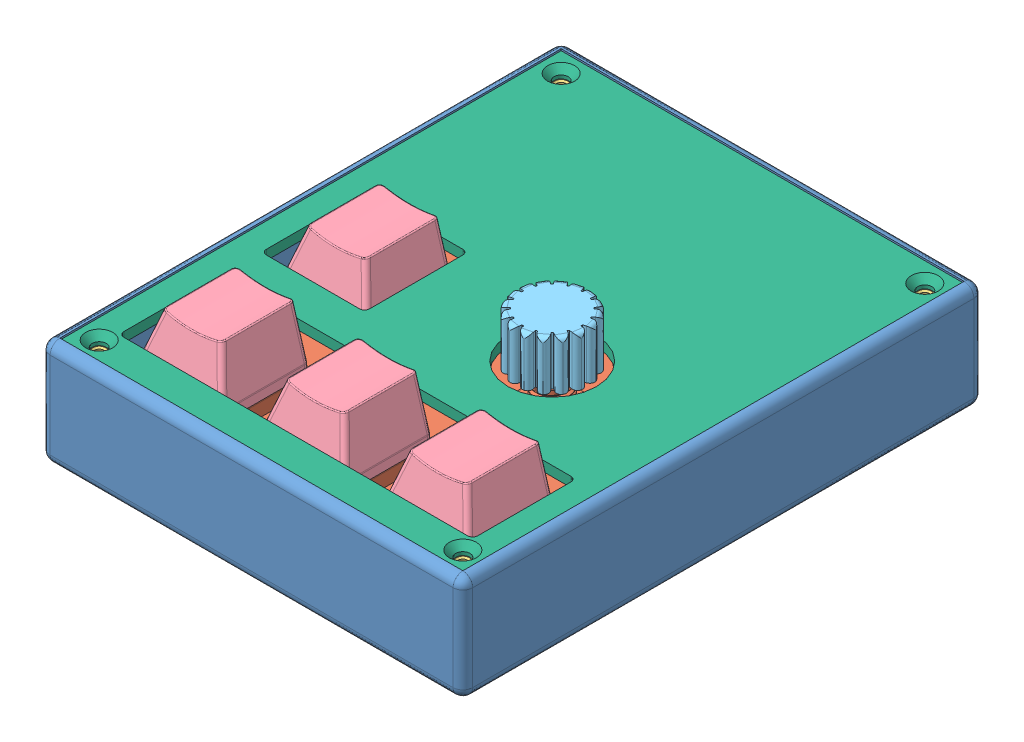
SolidWorks assembly DeviceAssembly, configuration Default. Lengths in mm.
Overall size (86 40.81 106).
12 component instances, 6 part files, 28 mates.
Components (placement in the parent):
- Box-1: Box [Default] at (-7.8946 4.0891 -4.0473) size (86 21.6 106)
- PCB-1: PCB [Default] at (-47.8946 11.3353 -54.0503) x (1 0 0) z (0 1 0) size (80 100.71 38.82)
- Standoff-1: Standoff [Default] at (-44.8946 21.3353 -51.0473) x (-0.059486 0 0.998229) z (0 -1 0) size (5.78 5.78 16)
- Standoff-13: Standoff [Default] at (-44.8946 21.3353 42.9527) x (0.129701 0 0.991553) z (0 -1 0) size (5.78 5.78 16)
- Standoff-15: Standoff [Default] at (29.1054 21.3353 42.9527) x (0.340404 0 0.940279) z (0 -1 0) size (5.78 5.78 16)
- Standoff-17: Standoff [Default] at (29.1054 21.3353 -51.0473) x (0.551349 0 0.834275) z (0 -1 0) size (5.78 5.78 16)
- Keycap-1: Keycap [Default] at (-42.1246 16.9831 -8.5326) x (1 0 0) z (0 0 1) size (18 11.34 18.01)
- Keycap-2: Keycap [Default] at (-42.1246 16.9831 20.8162) x (1 0 0) z (0 0 1) size (18 11.34 18.01)
- Keycap-4: Keycap [Default] at (-17.1246 16.9831 20.8162) x (1 0 0) z (0 0 1) size (18 11.34 18.01)
- Keycap-6: Keycap [Default] at (7.8754 16.9831 20.8162) x (1 0 0) z (0 0 1) size (18 11.34 18.01)
- Knob cap-1: Knob cap [Default] at (-22.2739 22.648 -63.0567) x (-0.249245 0 -0.96844) z (0 1 0) size (14.94 14.94 10)
- Lid-1: Lid [Default] at (0.6036 21.3353 0.6796) x (1 0 0) z (0 1 0) size (82 102 2)
Mates (geometry in assembly coordinates):
- Distance1: distance = 1 mm anti-aligned: plane of PCB-1 through (-47.8946 10.0891 42.9527) normal (-1 0 0); plane of Box-1 through (-48.8946 23.6891 -55.0473) normal (1 0 0)
- Distance2: distance = 1 mm anti-aligned: plane of PCB-1 through (-44.8946 10.0891 -54.0473) normal (0 0 -1); plane of Box-1 through (-48.8946 23.6891 -55.0473) normal (0 0 1)
- Distance3: distance = 0 mm anti-aligned: plane of PCB-1 through (-7.8946 10.0891 -4.0475) normal (0 -1 0); plane of Box-1 through (-7.8946 10.0891 -4.0473) normal (0 1 0)
- Concentric3: concentric aligned: cylinder of Box-1 through (-44.8946 10.0891 -51.0473) axis (0 -1 0) radius 1.85; cylinder of Standoff-1 through (-44.8946 21.3353 -51.0473) axis (0 -1 0) radius 1.25
- Coincident8: coincident anti-aligned: plane of PCB-1 through (-7.8946 11.3353 -4.0475) normal (0 1 0); plane of Standoff-1 through (-44.8946 11.3353 -51.0473) normal (0 -1 0)
- Concentric9: concentric aligned: cylinder of Box-1 through (-44.8946 10.0891 42.9527) axis (0 -1 0) radius 1.85; cylinder of Standoff-13 through (-44.8946 21.3353 42.9527) axis (0 -1 0) radius 1.25
- Coincident19: coincident anti-aligned: plane of PCB-1 through (-7.8946 11.3353 -4.0475) normal (0 1 0); plane of Standoff-13 through (-44.8946 11.3353 42.9527) normal (0 -1 0)
- Concentric10: concentric aligned: cylinder of Box-1 through (29.1054 10.0891 42.9527) axis (0 -1 0) radius 1.85; cylinder of Standoff-15 through (29.1054 21.3353 42.9527) axis (0 -1 0) radius 1.25
- Coincident20: coincident anti-aligned: plane of PCB-1 through (-7.8946 11.3353 -4.0475) normal (0 1 0); plane of Standoff-15 through (29.1054 11.3353 42.9527) normal (0 -1 0)
- Concentric11: concentric aligned: cylinder of Box-1 through (29.1054 10.0891 -51.0473) axis (0 -1 0) radius 1.85; cylinder of Standoff-17 through (29.1054 21.3353 -51.0473) axis (0 -1 0) radius 1.25
- Coincident21: coincident anti-aligned: plane of PCB-1 through (-7.8946 11.3353 -4.0475) normal (0 1 0); plane of Standoff-17 through (29.1054 11.3353 -51.0473) normal (0 -1 0)
- Distance7: distance = 0 mm anti-aligned: plane of PCB-1 through (-30.9746 22.4631 -0.0076) normal (1 0 0); plane of Keycap-1 through (-30.9746 28.4246 -0.1576) normal (-1 0 0)
- Coincident23: coincident anti-aligned: plane of PCB-1 through (-32.5496 22.4631 -1.6826) normal (0 0 -1); plane of Keycap-1 through (-32.4996 28.4246 -1.6826) normal (0 0 1)
- Tangent3: tangent anti-aligned: plane of PCB-1 through (-33.2246 26.0831 0.5674) normal (0 1 0); face of Keycap-1
- Distance8: distance = 0 mm anti-aligned: plane of PCB-1 through (-30.9746 22.4631 29.3412) normal (1 0 0); plane of Keycap-2 through (-30.9746 28.4246 29.1912) normal (-1 0 0)
- Coincident24: coincident anti-aligned: plane of PCB-1 through (-32.5496 22.4631 27.6662) normal (0 0 -1); plane of Keycap-2 through (-32.4996 28.4246 27.6662) normal (0 0 1)
- Tangent4: tangent anti-aligned: plane of PCB-1 through (-33.2246 26.0831 29.9162) normal (0 1 0); edge_curve of Keycap-2
- Distance9: distance = 0 mm anti-aligned: plane of PCB-1 through (-5.9746 22.4631 29.3412) normal (1 0 0); plane of Keycap-4 through (-5.9746 28.4246 29.1912) normal (-1 0 0)
- Coincident25: coincident anti-aligned: plane of PCB-1 through (-7.5496 22.4631 27.6662) normal (0 0 -1); plane of Keycap-4 through (-7.4996 28.4246 27.6662) normal (0 0 1)
- Tangent5: tangent anti-aligned: plane of PCB-1 through (-8.2246 26.0831 29.9162) normal (0 1 0); edge_curve of Keycap-4
- Distance10: distance = 0 mm anti-aligned: plane of PCB-1 through (19.0254 22.4631 29.3412) normal (1 0 0); plane of Keycap-6 through (19.0254 28.4246 29.1912) normal (-1 0 0)
- Coincident26: coincident anti-aligned: plane of PCB-1 through (17.4504 22.4631 27.6662) normal (0 0 -1); plane of Keycap-6 through (17.5004 28.4246 27.6662) normal (0 0 1)
- Tangent6: tangent anti-aligned: plane of PCB-1 through (16.7754 26.0831 29.9162) normal (0 1 0); edge_curve of Keycap-6
- Distance12: distance = 0 mm anti-aligned: plane of Knob cap-1 through (4.9054 30.648 0.5674) normal (0 -1 0); plane of PCB-1 through (1.9054 30.648 0.5674) normal (0 1 0)
- Concentric12: concentric aligned: cylinder of PCB-1 through (4.9054 15.648 0.5674) axis (0 -1 0) radius 3; cylinder of Knob cap-1 through (4.9054 30.648 0.5674) axis (0 -1 0) radius 3.05
- Coincident37: coincident anti-aligned: plane of Standoff-13 through (-44.8946 21.3353 42.9527) normal (0 1 0); plane of Lid-1 through (0.6036 21.3353 0.6796) normal (0 -1 0)
- Coincident38: coincident anti-aligned: plane of Box-1 through (-48.8946 23.6891 -55.0473) normal (1 0 0); plane of Lid-1 through (-48.8946 23.3353 -55.0473) normal (-1 0 0)
- Coincident39: coincident anti-aligned: plane of Box-1 through (-48.8946 23.6891 46.9527) normal (0 0 -1); plane of Lid-1 through (-48.8946 23.3353 46.9527) normal (0 0 1)
